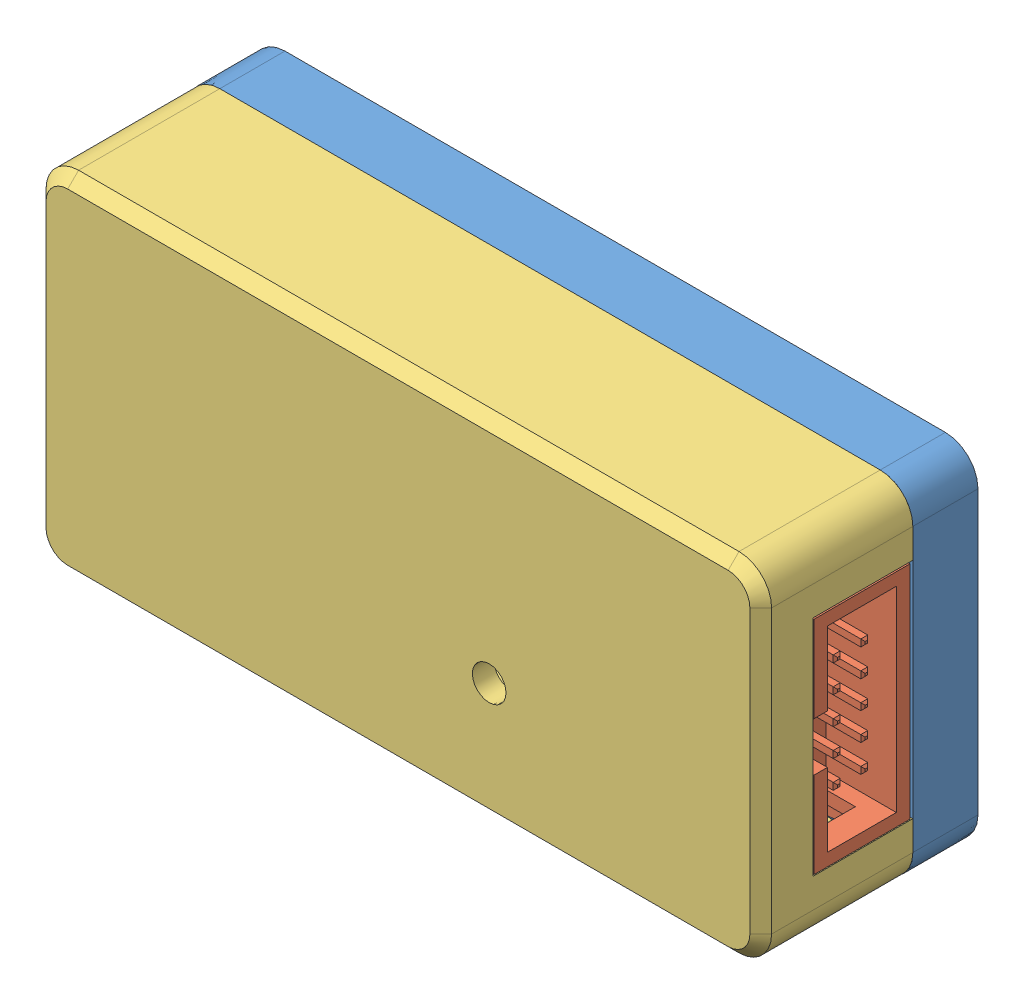
SolidWorks assembly asm-jlink-case, configuration По умолчанию. Lengths in mm.
Overall size (66.83 32 20).
3 component instances, 3 part files, 5 mates.
Components (placement in the parent):
- jlink-case-bottom-1: jlink-case-bottom [По умолчанию] at (-92.7123 1.8098 40.4055) size (66.8 32 6)
- jlink-1: jlink [По умолчанию] at (-90.7123 3.8098 44.8055) size (66.23 28 13.09)
- jlink-case-top-1: jlink-case-top [По умолчанию] at (-92.7123 33.8098 60.4055) x (1 0 0) z (0 0 -1) size (66.8 32 14)
Mates (geometry in assembly coordinates):
- Концентричный2: concentric anti-aligned: cylinder of jlink-case-bottom-1 through (-87.8123 28.9098 46.4055) axis (0 0 -1) radius 1.25; cylinder of jlink-1 through (-87.8123 28.9098 44.0055) axis (0 0 1) radius 1.25
- Совпадение2: coincident anti-aligned: plane of jlink-case-bottom-1 through (-87.6123 28.7098 44.8055) normal (0 0 1); plane of jlink-1 through (-60.7123 17.8098 44.8055) normal (0 0 -1)
- Параллельность2: parallel aligned: plane of jlink-case-bottom-1 through (-28.9123 4.8098 46.4055) normal (0 0 1); plane of jlink-case-top-1 through (-28.9123 30.8098 60.4055) normal (0 0 1)
- Параллельность3: parallel aligned: plane of jlink-case-bottom-1 through (-89.7123 1.8098 46.4055) normal (0 -1 0); plane of jlink-case-top-1 through (-89.7123 1.8098 46.4055) normal (0 -1 0)
- Совпадение4: coincident: point of jlink-case-bottom-1; point of jlink-case-top-1
